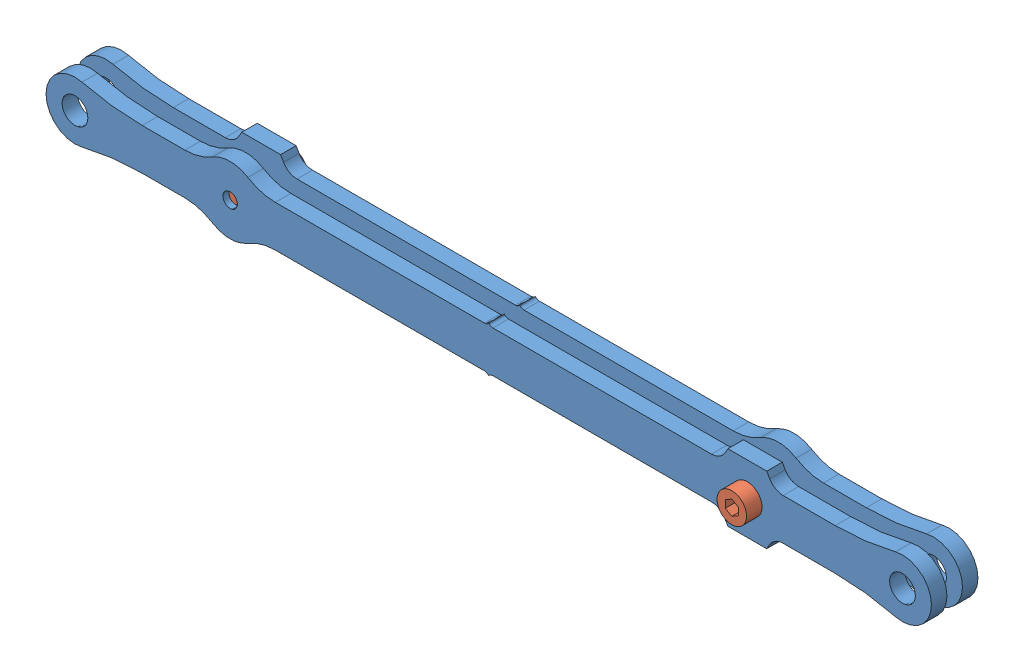
SolidWorks assembly ball-ended-rod, configuration Default. Lengths in mm.
Overall size (171.2 13 15).
4 component instances, 2 part files, 7 mates.
Components (placement in the parent):
- 1232-1: 1232 [Default] at (53.9278 105.2837 170.0022) size (171.2 13 3)
- 1232-2: 1232 [Default] at (53.9278 105.2837 167.0022) x (-1 0 0) z (0 0 -1) size (171.2 13 3)
- 111-5: 111 [Default] at (103.9278 105.2837 173.0022) size (5.7 5.7 11)
- 111-4: 111 [Default] at (3.9278 105.2837 164.0022) x (0.931866 0.362802 0) z (0 0 -1) size (5.7 5.7 11)
Mates (geometry in assembly coordinates):
- Coincident6: coincident anti-aligned: plane of 1232-1 through (133.9278 105.2837 173.0022) normal (0 0 1); plane of 111-5 through (103.9278 105.2837 173.0022) normal (0 0 -1)
- Distance1: distance = 3 mm anti-aligned: plane of 1232-1 through (133.9278 105.2837 170.0022) normal (0 0 -1); plane of 1232-2 through (-26.0722 105.2837 167.0022) normal (0 0 1)
- Concentric16: concentric anti-aligned: cylinder of 1232-1 through (3.9278 105.2837 170.0022) axis (0 0 1) radius 1.4; cylinder of 111-4 through (3.9278 105.2837 172.0022) axis (0 0 -1) radius 1.5
- Coincident12: coincident anti-aligned: plane of 1232-2 through (-26.0722 105.2837 164.0022) normal (0 0 -1); plane of 111-4 through (3.9278 105.2837 164.0022) normal (0 0 1)
- Concentric17: concentric aligned: line of 1232-1 through (103.9278 105.2837 173.1522) axis (0 0 -1); cylinder of 1232-2 through (103.9278 105.2837 167.0022) axis (0 0 -1) radius 1.4
- Concentric18: concentric aligned: cylinder of 1232-1 through (3.9278 105.2837 170.0022) axis (0 0 1) radius 6.5; line of 1232-2 through (3.9278 105.2837 163.8522) axis (0 0 1)
- Concentric19: concentric anti-aligned: cylinder of 1232-2 through (103.9278 105.2837 167.0022) axis (0 0 -1) radius 1.4; cylinder of 111-5 through (103.9278 105.2837 165.0022) axis (0 0 1) radius 1.5
